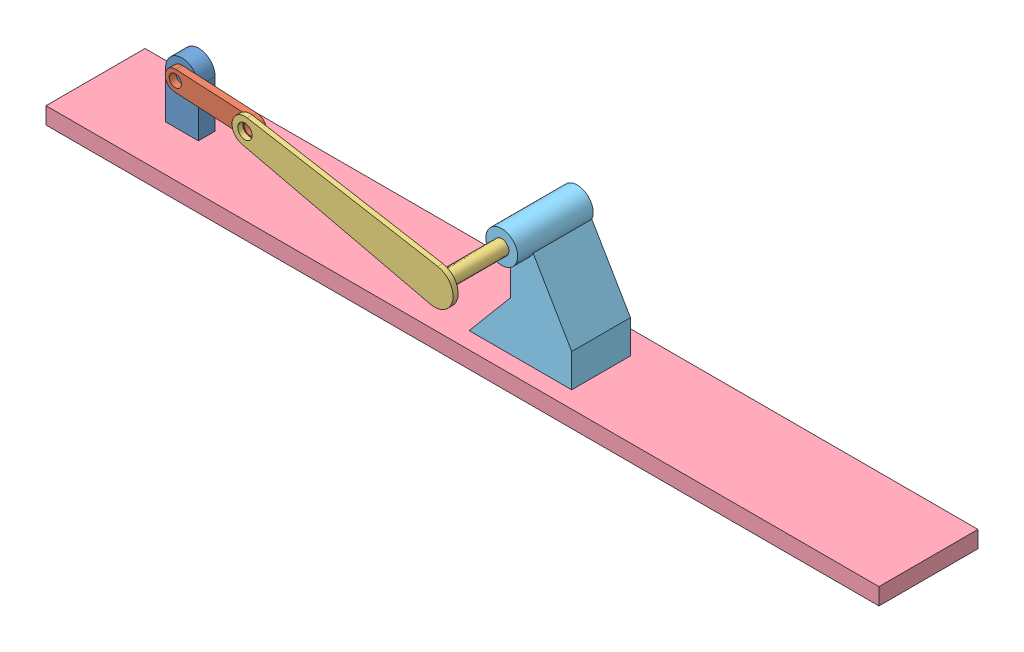
SolidWorks assembly SliderCrank, configuration Default. Lengths in mm.
Overall size (496.37 148.35 99.01).
5 component instances, 5 part files, 7 mates.
Components (placement in the parent):
- BasePart-1: BasePart [Default] at (-17.8342 -13.5965 12.4769) size (19.5 37.91 10)
- Crank-1: Crank [Default] at (-26.3254 14.429 19.4769) x (0.776959 -0.629551 0) z (0 0 1) size (48.08 38.15 4)
- Slider-1: Slider [Default] at (65.6721 -29.0715 21.4769) x (0.895375 0.445314 0) z (0 0 1) size (109.69 89.86 57)
- Ground-1: Ground [Default] at (-8.8704 -73.8544 -50.3062) size (496.37 10 59.01)
- MotionPart-1: MotionPart [Default] at (65.3626 -3.039 -25.5231) x (-1 0 0) z (0 0 -1) size (61.08 72.38 45)
Mates (geometry in assembly coordinates):
- Concentric1: concentric aligned: cylinder of BasePart-1; cylinder of Crank-1
- Coincident1: coincident anti-aligned: plane of BasePart-1 through (-17.8342 14.5607 17.4769) normal (0 0 1); plane of Crank-1 through (-17.8342 14.5607 17.4769) normal (0 0 -1)
- Concentric5: concentric aligned: cylinder of Slider-1; cylinder of MotionPart-1
- Distance3: distance = 40 mm aligned: plane of Slider-1 through (26.6483 12.1641 24.4769) normal (0 0 1); plane of MotionPart-1 through (139.6784 -10.989 -15.5231) normal (0 0 1)
- Coincident7: coincident anti-aligned: plane of Ground-1 through (-131.8814 -73.8544 -15.5231) normal (0 1 0); plane of MotionPart-1 through (171.3823 -73.8544 -60.5231) normal (0 -1 0)
- Perpendicular1: perpendicular: plane of Crank-1 through (-17.8342 14.5607 21.4769) normal (0 0 1); plane of Slider-1 through (24.8784 4.6336 24.4769) normal (-0.2288 -0.973473 0)
- Coincident8: coincident: point of Crank-1; point of Slider-1
